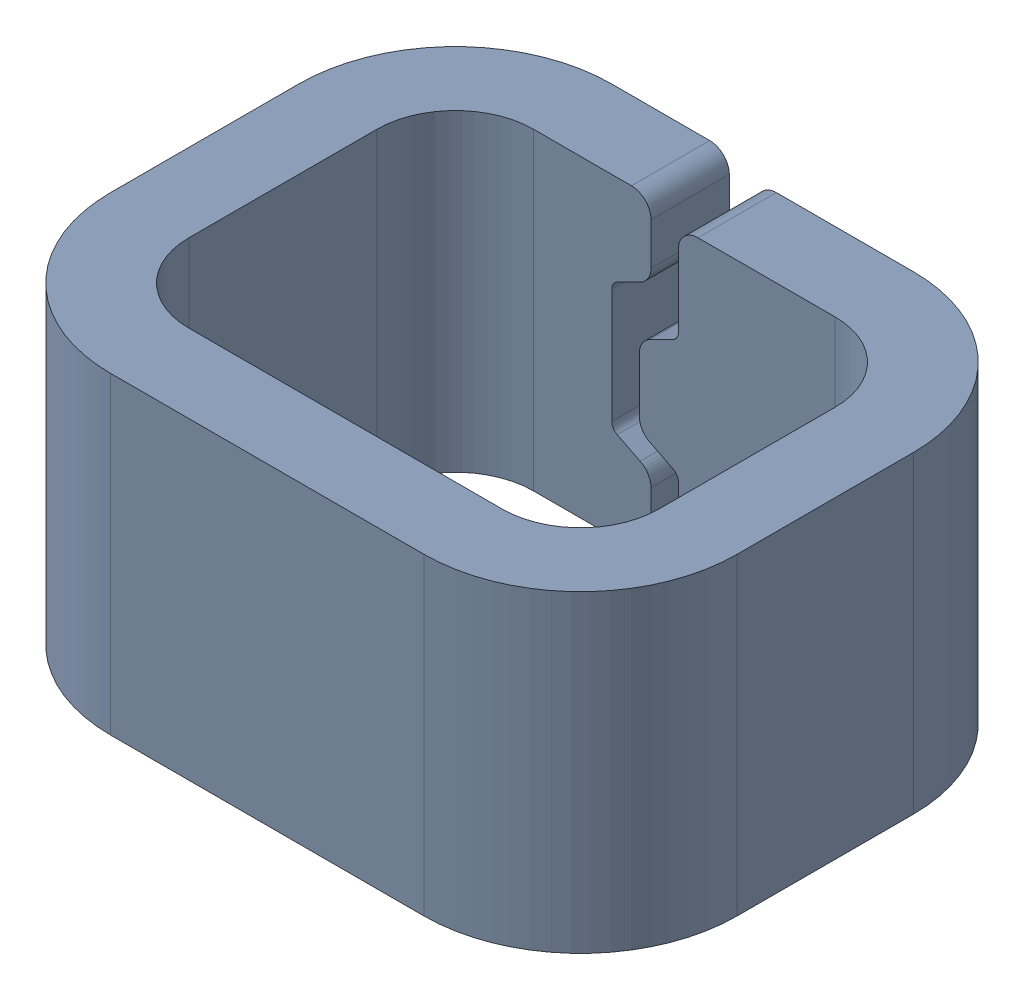
SolidWorks assembly TP4, configuration Default. Lengths in mm.
Overall size (1.6 0.8 1.28).
2 component instances, 1 part files, 0 mates.
Components (placement in the parent):
- Conn_Harwin_S2761-46R_eec-1: Conn_Harwin_S2761-46R_eec [Default] at (29.21 8.382 0) x (-1 0 0) z (0 0 1) size (1.6 0.8 1.28)
  - TP-1: TP [Default] at origin size (1.6 0.8 1.28)
